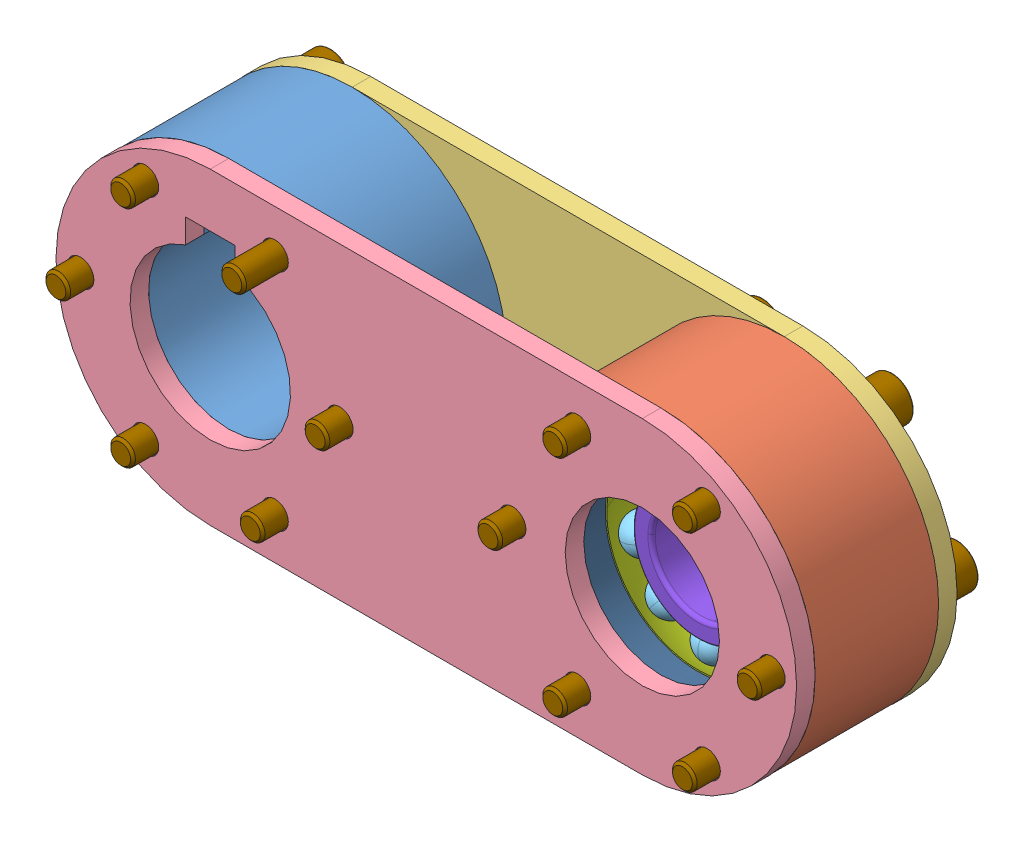
SolidWorks assembly manivela con rodamiento derecha, configuration Predeterminado. Lengths in mm.
Overall size (120 50 37).
40 component instances, 10 part files, 37 mates.
Components (placement in the parent):
- cople flecha-1: cople flecha [Predeterminado] at origin size (50 50 20)
- cople rodamiento-1: cople rodamiento [Predeterminado] at (70 0 0) size (50 50 20)
- placa manivela 2-3: placa manivela 2 [Predeterminado] at (0 0 -3) size (120 50 3)
- placa manivela-2: placa manivela [Predeterminado] at (0 0 20) size (120 50 3)
- 2202_ETN9-1: 2202_ETN9 [Default] at (70 0 14) x (0 0 -1) z (0.269918 -0.962883 0) size (14 35 35)
  - 2202_ETN9_3-1: 2202_ETN9_3 [Default] x (1 0 0) z (0 -0.587785 0.809017) size (6 6 6)
  - 2202_ETN9_3-2: 2202_ETN9_3 [Default] x (1 0 0) z (0 -0.951057 0.309017) size (6 6 6)
  - 2202_ETN9_3-3: 2202_ETN9_3 [Default] x (1 0 0) z (0 -0.951057 -0.309017) size (6 6 6)
  - 2202_ETN9_3-4: 2202_ETN9_3 [Default] x (1 0 0) z (0 -0.587785 -0.809017) size (6 6 6)
  - 2202_ETN9_3-5: 2202_ETN9_3 [Default] x (1 0 0) z (0 0 -1) size (6 6 6)
  - 2202_ETN9_3-6: 2202_ETN9_3 [Default] x (1 0 0) z (0 0.587785 -0.809017) size (6 6 6)
  - 2202_ETN9_3-7: 2202_ETN9_3 [Default] x (1 0 0) z (0 0.951057 -0.309017) size (6 6 6)
  - 2202_ETN9_3-8: 2202_ETN9_3 [Default] x (1 0 0) z (0 0.951057 0.309017) size (6 6 6)
  - 2202_ETN9_3-9: 2202_ETN9_3 [Default] x (1 0 0) z (0 0.587785 0.809017) size (6 6 6)
  - 2202_ETN9_3-10: 2202_ETN9_3 [Default] at origin size (6 6 6)
  - 2202_ETN9_14-1: 2202_ETN9_14 [Default] x (1 0 0) z (0 -0.587785 0.809017) size (6 6 6)
  - 2202_ETN9_14-2: 2202_ETN9_14 [Default] x (1 0 0) z (0 -0.951057 0.309017) size (6 6 6)
  - 2202_ETN9_14-3: 2202_ETN9_14 [Default] x (1 0 0) z (0 -0.951057 -0.309017) size (6 6 6)
  - 2202_ETN9_14-4: 2202_ETN9_14 [Default] x (1 0 0) z (0 -0.587785 -0.809017) size (6 6 6)
  - 2202_ETN9_14-5: 2202_ETN9_14 [Default] x (1 0 0) z (0 0 -1) size (6 6 6)
  - 2202_ETN9_14-6: 2202_ETN9_14 [Default] x (1 0 0) z (0 0.587785 -0.809017) size (6 6 6)
  - 2202_ETN9_14-7: 2202_ETN9_14 [Default] x (1 0 0) z (0 0.951057 -0.309017) size (6 6 6)
  - 2202_ETN9_14-8: 2202_ETN9_14 [Default] x (1 0 0) z (0 0.951057 0.309017) size (6 6 6)
  - 2202_ETN9_14-9: 2202_ETN9_14 [Default] x (1 0 0) z (0 0.587785 0.809017) size (6 6 6)
  - 2202_ETN9_14-10: 2202_ETN9_14 [Default] at origin size (6 6 6)
  - 2202_ETN9_29-1: 2202_ETN9_29 [Default] at origin size (14 35 35)
  - 2202_ETN9_31-1: 2202_ETN9_31 [Default] at origin size (14 20.86 20.86)
- socket head cap screw_iso-29: socket head cap screw_iso [ISO 4762 M4 x 30 - 20N] at (-10.5 18.1865 -7) x (0 0 1) z (-1 0 0) size (34 7 7)
- socket head cap screw_iso-30: socket head cap screw_iso [ISO 4762 M4 x 30 - 20N] at (10.5 18.1865 -4) x (0 0 1) z (-1 0 0) size (34 7 7)
- socket head cap screw_iso-31: socket head cap screw_iso [ISO 4762 M4 x 30 - 20N] at (21 0 -7) x (0 0 1) z (-1 0 0) size (34 7 7)
- socket head cap screw_iso-32: socket head cap screw_iso [ISO 4762 M4 x 30 - 20N] at (10.5 -18.1865 -7) x (0 0 1) z (-1 0 0) size (34 7 7)
- socket head cap screw_iso-33: socket head cap screw_iso [ISO 4762 M4 x 30 - 20N] at (-10.5 -18.1865 -7) x (0 0 1) z (-1 0 0) size (34 7 7)
- socket head cap screw_iso-34: socket head cap screw_iso [ISO 4762 M4 x 30 - 20N] at (-21 0 -7) x (0 0 1) z (-1 0 0) size (34 7 7)
- socket head cap screw_iso-35: socket head cap screw_iso [ISO 4762 M4 x 30 - 20N] at (49 0 -7) x (0 0 1) z (-1 0 0) size (34 7 7)
- socket head cap screw_iso-36: socket head cap screw_iso [ISO 4762 M4 x 30 - 20N] at (59.5 18.1865 -7) x (0 0 1) z (-1 0 0) size (34 7 7)
- socket head cap screw_iso-37: socket head cap screw_iso [ISO 4762 M4 x 30 - 20N] at (80.5 18.1865 -7) x (0 0 1) z (-1 0 0) size (34 7 7)
- socket head cap screw_iso-38: socket head cap screw_iso [ISO 4762 M4 x 30 - 20N] at (91 0 -7) x (0 0 1) z (-1 0 0) size (34 7 7)
- socket head cap screw_iso-39: socket head cap screw_iso [ISO 4762 M4 x 30 - 20N] at (80.5 -18.1865 -7) x (0 0 1) z (-1 0 0) size (34 7 7)
- socket head cap screw_iso-40: socket head cap screw_iso [ISO 4762 M4 x 30 - 20N] at (59.5 -18.1865 -7) x (0 0 1) z (-1 0 0) size (34 7 7)
- anillo manivela-1: anillo manivela [Predeterminado] at (70 0 14) size (35 35 6)
Mates (geometry in assembly coordinates):
- Coincidente1: coincident anti-aligned: plane of cople flecha-1 through (0 0 0) normal (0 0 -1); plane of placa manivela 2-3 through (0 0 0) normal (0 0 1)
- Concéntrica1: concentric aligned: cylinder of cople flecha-1 through (0 0 0) axis (0 0 1) radius 13; cylinder of placa manivela 2-3 through (0 0 0) axis (0 0 1) radius 2.65
- Concéntrica2: concentric aligned: cylinder of cople flecha-1 through (-10.5 18.1865 20) axis (0 0 1) radius 2.15; cylinder of placa manivela 2-3 through (-10.5 18.1865 0) axis (0 0 1) radius 2.15
- Concéntrica3: concentric anti-aligned: circle of cople rodamiento-1; cylinder of 2202_ETN9-1/2202_ETN9_29-1 through (70 0 -36) axis (0 0 -1) radius 17.5
- Coincidente4: coincident anti-aligned: plane of cople rodamiento-1 through (70 0 0) normal (0 0 -1); plane of placa manivela 2-3 through (0 0 0) normal (0 0 1)
- Concéntrica4: concentric aligned: cylinder of cople rodamiento-1 through (70 0 20) axis (0 0 -1) radius 25; cylinder of placa manivela 2-3 through (70 0 0) axis (0 0 -1) radius 25
- Concéntrica5: concentric aligned: cylinder of cople rodamiento-1 through (91 0 20) axis (0 0 1) radius 2.15; cylinder of placa manivela 2-3 through (91 0 0) axis (0 0 1) radius 2.15
- Coincidente5: coincident anti-aligned: plane of cople flecha-1 through (0 0 20) normal (0 0 1); plane of placa manivela-2 through (0 0 20) normal (0 0 -1)
- Concéntrica6: concentric aligned: cylinder of cople flecha-1 through (0 0 0) axis (0 0 1) radius 13; cylinder of placa manivela-2 through (0 0 20) axis (0 0 1) radius 13
- Concéntrica7: concentric aligned: cylinder of cople rodamiento-1 through (59.5 18.1865 20) axis (0 0 1) radius 2.15; cylinder of placa manivela-2 through (59.5 18.1865 23) axis (0 0 1) radius 2.15
- Concéntrica8: concentric anti-aligned: cylinder of placa manivela 2-3 through (-10.5 18.1865 0) axis (0 0 1) radius 2.15; cylinder of socket head cap screw_iso-29 through (-10.5 18.1865 -38.75) axis (0 0 -1) radius 3.5
- Coincidente6: coincident anti-aligned: plane of placa manivela 2-3 through (0 0 -3) normal (0 0 -1); plane of socket head cap screw_iso-29 through (-10.5 21.6865 -3) normal (0 0 1)
- Concéntrica9: concentric anti-aligned: cylinder of cople flecha-1 through (10.5 18.1865 20) axis (0 0 1) radius 2.15; cylinder of socket head cap screw_iso-30 through (10.5 18.1865 -35.75) axis (0 0 -1) radius 3.5
- Coincidente7: coincident anti-aligned: plane of cople flecha-1 through (0 0 0) normal (0 0 -1); plane of socket head cap screw_iso-30 through (10.5 21.6865 0) normal (0 0 1)
- Concéntrica10: concentric anti-aligned: cylinder of placa manivela 2-3 through (21 0 0) axis (0 0 1) radius 2.15; cylinder of socket head cap screw_iso-31 through (21 0 -38.75) axis (0 0 -1) radius 3.5
- Coincidente8: coincident anti-aligned: plane of placa manivela 2-3 through (0 0 -3) normal (0 0 -1); plane of socket head cap screw_iso-31 through (21 3.5 -3) normal (0 0 1)
- Concéntrica11: concentric anti-aligned: cylinder of placa manivela 2-3 through (10.5 -18.1865 0) axis (0 0 1) radius 2.15; cylinder of socket head cap screw_iso-32 through (10.5 -18.1865 -38.75) axis (0 0 -1) radius 3.5
- Coincidente9: coincident anti-aligned: plane of placa manivela 2-3 through (0 0 -3) normal (0 0 -1); plane of socket head cap screw_iso-32 through (10.5 -14.6865 -3) normal (0 0 1)
- Concéntrica12: concentric anti-aligned: cylinder of placa manivela 2-3 through (-10.5 -18.1865 0) axis (0 0 1) radius 2.15; cylinder of socket head cap screw_iso-33 through (-10.5 -18.1865 -38.75) axis (0 0 -1) radius 3.5
- Coincidente10: coincident anti-aligned: plane of placa manivela 2-3 through (0 0 -3) normal (0 0 -1); plane of socket head cap screw_iso-33 through (-10.5 -14.6865 -3) normal (0 0 1)
- Concéntrica13: concentric anti-aligned: cylinder of placa manivela 2-3 through (-21 0 0) axis (0 0 1) radius 2.15; cylinder of socket head cap screw_iso-34 through (-21 0 -38.75) axis (0 0 -1) radius 3.5
- Coincidente11: coincident anti-aligned: plane of placa manivela 2-3 through (0 0 -3) normal (0 0 -1); plane of socket head cap screw_iso-34 through (-21 3.5 -3) normal (0 0 1)
- Concéntrica14: concentric anti-aligned: cylinder of placa manivela 2-3 through (49 0 0) axis (0 0 1) radius 2.15; cylinder of socket head cap screw_iso-35 through (49 0 -38.75) axis (0 0 -1) radius 3.5
- Coincidente12: coincident anti-aligned: plane of placa manivela 2-3 through (0 0 -3) normal (0 0 -1); plane of socket head cap screw_iso-35 through (49 3.5 -3) normal (0 0 1)
- Concéntrica15: concentric anti-aligned: cylinder of placa manivela 2-3 through (59.5 18.1865 0) axis (0 0 1) radius 2.15; cylinder of socket head cap screw_iso-36 through (59.5 18.1865 -38.75) axis (0 0 -1) radius 3.5
- Coincidente13: coincident anti-aligned: plane of placa manivela 2-3 through (0 0 -3) normal (0 0 -1); plane of socket head cap screw_iso-36 through (59.5 21.6865 -3) normal (0 0 1)
- Concéntrica16: concentric anti-aligned: cylinder of placa manivela 2-3 through (80.5 18.1865 0) axis (0 0 1) radius 2.15; cylinder of socket head cap screw_iso-37 through (80.5 18.1865 -38.75) axis (0 0 -1) radius 3.5
- Coincidente14: coincident anti-aligned: plane of placa manivela 2-3 through (0 0 -3) normal (0 0 -1); plane of socket head cap screw_iso-37 through (80.5 21.6865 -3) normal (0 0 1)
- Concéntrica17: concentric anti-aligned: cylinder of placa manivela 2-3 through (91 0 0) axis (0 0 1) radius 2.15; cylinder of socket head cap screw_iso-38 through (91 0 -38.75) axis (0 0 -1) radius 3.5
- Coincidente15: coincident anti-aligned: plane of placa manivela 2-3 through (0 0 -3) normal (0 0 -1); plane of socket head cap screw_iso-38 through (91 3.5 -3) normal (0 0 1)
- Concéntrica18: concentric anti-aligned: cylinder of placa manivela 2-3 through (80.5 -18.1865 0) axis (0 0 1) radius 2.15; cylinder of socket head cap screw_iso-39 through (80.5 -18.1865 -38.75) axis (0 0 -1) radius 3.5
- Coincidente16: coincident anti-aligned: plane of placa manivela 2-3 through (0 0 -3) normal (0 0 -1); plane of socket head cap screw_iso-39 through (80.5 -14.6865 -3) normal (0 0 1)
- Concéntrica19: concentric anti-aligned: cylinder of placa manivela 2-3 through (59.5 -18.1865 0) axis (0 0 1) radius 2.15; cylinder of socket head cap screw_iso-40 through (59.5 -18.1865 -38.75) axis (0 0 -1) radius 3.5
- Coincidente17: coincident anti-aligned: plane of placa manivela 2-3 through (0 0 -3) normal (0 0 -1); plane of socket head cap screw_iso-40 through (59.5 -14.6865 -3) normal (0 0 1)
- Coincidente18: coincident anti-aligned: plane of placa manivela 2-3 through (0 0 0) normal (0 0 1); plane of 2202_ETN9-1/2202_ETN9_29-1 through (84.2025 3.9813 0) normal (0 0 -1)
- Concéntrica20: concentric aligned: cylinder of cople rodamiento-1 through (70 0 20) axis (0 0 -1) radius 17.5; cylinder of anillo manivela-1 through (70 0 20) axis (0 0 -1) radius 17.5
- Coincidente19: coincident anti-aligned: plane of placa manivela-2 through (0 0 20) normal (0 0 -1); plane of anillo manivela-1 through (70 0 20) normal (0 0 1)
